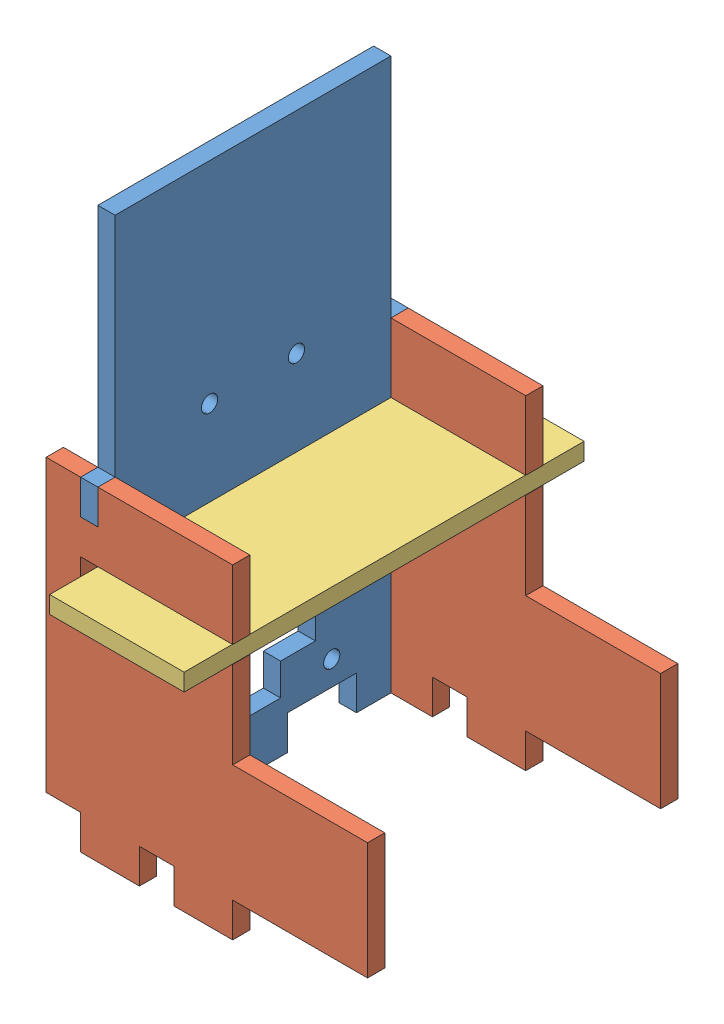
SolidWorks assembly preference_troughCoverAssembly, configuration Large. Lengths in mm.
Overall size (59.2 101.6 73.66).
4 component instances, 3 part files, 8 mates.
Components (placement in the parent):
- preference_troughCover_front-1: preference_troughCover_front [Default] at (-76.5195 65.487 128.4334)
- preference_troughCover_side-1: preference_troughCover_side [large] at (70.8305 87.458 103.0334) x (0 0 -1) z (1 0 0) size (3.17 59.82 59.2)
- preference_troughCover_side-2: preference_troughCover_side [large] at (70.8305 87.458 157.0084) x (0 0 -1) z (1 0 0) size (3.17 59.82 59.2)
- preference_troughCover_top-1: preference_troughCover_top [Default] at (60.0055 112.604 129.0565) x (0 0 1) z (1 0 0)
Mates (geometry in assembly coordinates):
- Coincident1: coincident anti-aligned: plane of preference_troughCover_front-1 through (56.8305 65.487 103.0334) normal (0 0 -1); plane of preference_troughCover_side-1 through (70.8305 87.458 103.0334) normal (0 0 1)
- Coincident2: coincident aligned: plane of preference_troughCover_front-1 through (-76.5195 65.487 128.4334) normal (0 -1 0); plane of preference_troughCover_side-1 through (70.8305 65.487 99.8584) normal (0 -1 0)
- Coincident4: coincident anti-aligned: plane of preference_troughCover_front-1 through (56.8305 65.487 153.8334) normal (0 0 1); plane of preference_troughCover_side-2 through (70.8305 87.458 153.8334) normal (0 0 -1)
- Coincident5: coincident aligned: plane of preference_troughCover_front-1 through (-76.5195 65.487 128.4334) normal (0 -1 0); plane of preference_troughCover_side-2 through (70.8305 65.487 153.8334) normal (0 -1 0)
- Coincident7: coincident aligned: plane of preference_troughCover_front-1 through (56.8305 370.287 61.7584) normal (-1 0 0); plane of preference_troughCover_top-1 through (56.8305 109.429 129.0565) normal (-1 0 0)
- Coincident8: coincident anti-aligned: plane of preference_troughCover_front-1 through (60.0055 109.429 128.4334) normal (0 1 0); plane of preference_troughCover_top-1 through (60.0055 109.429 129.0565) normal (0 -1 0)
- Coincident9: coincident anti-aligned: plane of preference_troughCover_front-1 through (56.8305 370.287 61.7584) normal (-1 0 0); plane of preference_troughCover_side-1 through (56.8305 87.458 99.8584) normal (1 0 0)
- Coincident10: coincident anti-aligned: plane of preference_troughCover_front-1 through (56.8305 370.287 61.7584) normal (-1 0 0); plane of preference_troughCover_side-2 through (56.8305 87.458 153.8334) normal (1 0 0)
